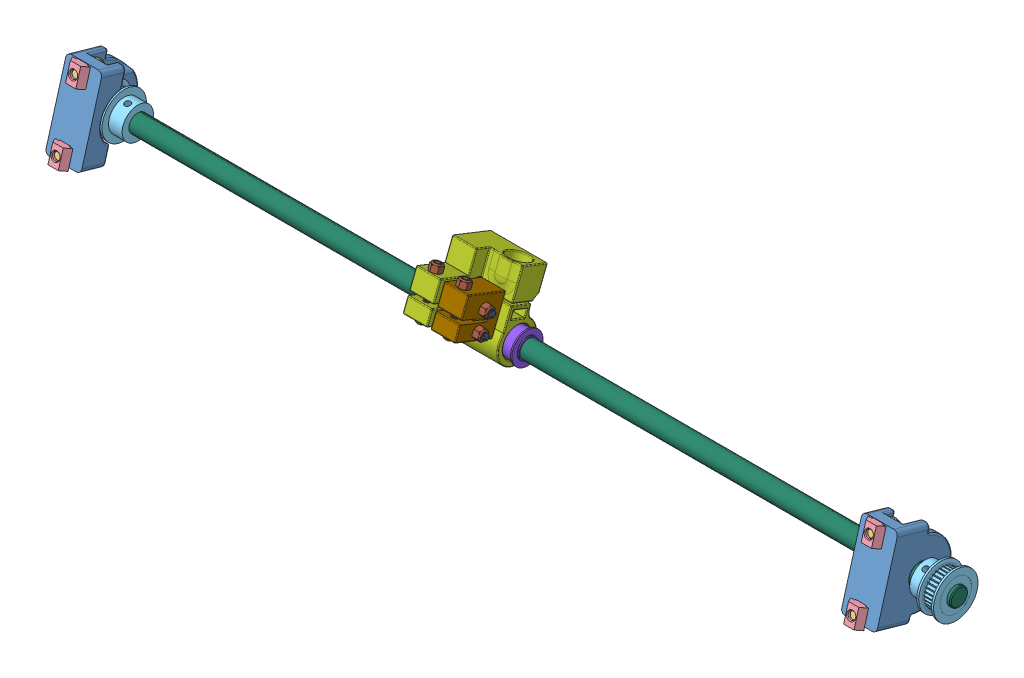
SolidWorks assembly XY_Axis_B, configuration Driven Axis. Lengths in mm.
Overall size (487 72.97 60.62).
36 component instances, 16 part files, 12 mates.
Components (placement in the parent):
- SFJ10-458-1: SFJ10-458 [Default] at origin size (458 10 10) (suppressed, hidden)
- 10mm_Rod_End_Bearing_Assembly-1: 10mm_Rod_End_Bearing_Assembly [Default] at (6 5.178 18.2808) x (0 -0.962148 0.272529) z (0 -0.272529 -0.962148) size (48.98 27.53 42.5)
  - Bearing_Holder-1: Bearing_Holder [Default] at origin size (45 20.07 37)
  - 6900ZZ_10x22x6-1: 6900ZZ_10x22x6 [5972K164] at (0 3 19) x (1 0 0) z (0 1 0) size (22 22 6)
  - 5mmX12mm_Buttonhead(McMaster_92095A210)-3: 5mmX12mm_Buttonhead(McMaster_92095A210) [92095A210] at (18 0 10.75) x (-0.866025 -0.5 0) z (0 0 1) size (9.5 9.5 15.22)
  - 5mmX12mm_Buttonhead(McMaster_92095A210)-2: 5mmX12mm_Buttonhead(McMaster_92095A210) [92095A210] at (-18 0 10.75) x (0.866025 0.5 0) z (0 0 1) size (9.5 9.5 15.22)
  - HNTTSN5-5-1: HNTTSN5-5 [Default] at (-18 0 -1.2) x (0 0 1) z (-1 0 0) size (4.3 10 10)
  - HNTTSN5-5-2: HNTTSN5-5 [Default] at (18 0 -1.2) x (0 0 1) z (-1 0 0) size (4.3 10 10)
  - GT2_Aluminum_Timing_Pulley_32_Tooth-1: GT2_Aluminum_Timing_Pulley_32_Tooth [Default] at (0 -0.5 19) x (0 -1 0) z (0.46829 0 -0.883575) size (17.03 24.87 24.87)
  - 10mmx16mmx0.5mm_SHim(McMaster_90214A422)-1: 10mmx16mmx0.5mm_SHim(McMaster_90214A422) [Default] at (0 -0.5 19) x (1 0 0) z (0 1 0) size (16 16 0.5)
- 10mm_Rod_End_Bearing_Assembly-2: 10mm_Rod_End_Bearing_Assembly [Pass Through Version] at (451 5.178 18.2808) x (0 0.962148 -0.272529) z (0 -0.272529 -0.962148) size (48.98 27.53 42.5)
  - Bearing_Holder-1: Bearing_Holder [Passthrough] at origin size (45 20.07 37)
  - 6900ZZ_10x22x6-1: 6900ZZ_10x22x6 [5972K164] at (0 3 19) x (1 0 0) z (0 1 0) size (22 22 6)
  - 5mmX12mm_Buttonhead(McMaster_92095A210)-3: 5mmX12mm_Buttonhead(McMaster_92095A210) [92095A210] at (18 0 10.75) x (-0.866025 -0.5 0) z (0 0 1) size (9.5 9.5 15.22)
  - 5mmX12mm_Buttonhead(McMaster_92095A210)-2: 5mmX12mm_Buttonhead(McMaster_92095A210) [92095A210] at (-18 0 10.75) x (0.866025 0.5 0) z (0 0 1) size (9.5 9.5 15.22)
  - HNTTSN5-5-1: HNTTSN5-5 [Default] at (-18 0 -1.2) x (0 0 1) z (-1 0 0) size (4.3 10 10)
  - HNTTSN5-5-2: HNTTSN5-5 [Default] at (18 0 -1.2) x (0 0 1) z (-1 0 0) size (4.3 10 10)
  - GT2_Aluminum_Timing_Pulley_32_Tooth-1: GT2_Aluminum_Timing_Pulley_32_Tooth [Default] at (0 -0.5 19) x (0 -1 0) z (0.46829 0 -0.883575) size (17.03 24.87 24.87)
  - 10mmx16mmx0.5mm_SHim(McMaster_90214A422)-1: 10mmx16mmx0.5mm_SHim(McMaster_90214A422) [Default] at (0 -0.5 19) x (1 0 0) z (0 1 0) size (16 16 0.5)
- XY_Axis_Belt_Tensioner_B-1: XY_Axis_Belt_Tensioner_B [Default] at (187.7262 29.7805 -17.15) x (0 0.367652 0.929963) z (1 0 0) size (46.04 45 41.58)
  - XY Axis Belt Tensioner B-1: XY Axis Belt Tensioner B [Default] at origin size (46 45 32.06)
  - a_7z41mpsb10m-1: a_7z41mpsb10m [Default] at (5 34 53.6866) x (1 0 0) z (0 1 0) size (17.4 11.55 17.4)
  - a_7z41mpsb10m-2: a_7z41mpsb10m [Default] at (5 34 15.25) x (1 0 0) z (0 -1 0) size (17.4 11.55 17.4)
  - XY Axis Belt Tensioner End-1: XY Axis Belt Tensioner End [Default] at (0 0 29.2) size (22.6 21 13.6)
  - 3mmX35mm_Sockethead(McMaster_91290A135)-1: 3mmX35mm_Sockethead(McMaster_91290A135) [91290A135] at (28.1 28.85 51) size (5.5 5.5 38.26)
  - 3mmX35mm_Sockethead(McMaster_91290A135)-2: 3mmX35mm_Sockethead(McMaster_91290A135) [91290A135] at (28.1 18.85 51) size (5.5 5.5 38.26)
  - 3mm_Hex_Nylock_Nut(McMaster_90576A102)-1: 3mm_Hex_Nylock_Nut(McMaster_90576A102) [90576A102] at (28.1 28.85 45.2) x (1 0 0) z (0 -1 0) size (5.5 4.1 6.35)
  - 3mm_Hex_Nylock_Nut(McMaster_90576A102)-2: 3mm_Hex_Nylock_Nut(McMaster_90576A102) [90576A102] at (28.1 18.85 45.2) x (1 0 0) z (0 -1 0) size (5.5 4.1 6.35)
  - 3mmX25mm_Buttonhead(McMaster_91239A126)-1: 3mmX25mm_Buttonhead(McMaster_91239A126) [91239A126] at (36 34.5 38.4) x (1 0 0) z (0 1 0) size (5.7 5.7 27.01)
  - 3mmX25mm_Buttonhead(McMaster_91239A126)-2: 3mmX25mm_Buttonhead(McMaster_91239A126) [91239A126] at (36 34.5 22.8) x (1 0 0) z (0 1 0) size (5.7 5.7 27.01)
  - 3mm_Hex_Nylock_Nut(McMaster_90576A102)-3: 3mm_Hex_Nylock_Nut(McMaster_90576A102) [90576A102] at (36 11.85 22.8) x (-0.89673 0 -0.442578) z (-0.442578 0 0.89673) size (5.5 4.1 6.35)
  - 3mm_Hex_Nylock_Nut(McMaster_90576A102)-4: 3mm_Hex_Nylock_Nut(McMaster_90576A102) [90576A102] at (36 11.85 38.4) x (-0.836969 0 -0.54725) z (-0.54725 0 0.836969) size (5.5 4.1 6.35)
  - 5mm_Hex_Nut(McMaster_90591A146)-1: 5mm_Hex_Nut(McMaster_90591A146) [90591A146] at (8.7 21.5 39.6) size (8 4.31 9.24)
  - 5mmX16mm_Buttonhead(McMaster_91239A232)-1: 5mmX16mm_Buttonhead(McMaster_91239A232) [91239A232] at (8.7 3.25 39.6) x (-0.995484 0 0.094925) z (0 -1 0) size (9.5 9.5 19.24)
- SFJ10-483-1: SFJ10-483 [Default] at origin
- GT2_Aluminum_Timing_Pulley_32_Tooth-1: GT2_Aluminum_Timing_Pulley_32_Tooth [Default] at (481.0004 0 0) x (-1 0 0) z (0 -0.913908 -0.405921) size (17.03 24.87 24.87)
Mates (geometry in assembly coordinates):
- Concentric1: concentric aligned: cylinder of SFJ10-458-1 through (458 0 0) axis (-1 0 0) radius 5; cylinder of 10mm_Rod_End_Bearing_Assembly-1/6900ZZ_10x22x6-1 through (0.5 0 0) axis (-1 0 0) radius 5
- Concentric2: concentric anti-aligned: cylinder of SFJ10-458-1 through (458 0 0) axis (-1 0 0) radius 5; cylinder of ? through (457.5 0 0) axis (1 0 0) radius 5
- Distance1: distance = 425 mm anti-aligned: plane of 10mm_Rod_End_Bearing_Assembly-1/Bearing_Holder-1 through (16 14.3374 -22.7692) normal (1 0 0); plane of 10mm_Rod_End_Bearing_Assembly-2/Bearing_Holder-1 through (441 -24.1485 -11.8681) normal (-1 0 0)
- Distance2: distance = 212.5 mm anti-aligned: plane of 10mm_Rod_End_Bearing_Assembly-1/Bearing_Holder-1 through (16.5 22.3708 -14.9514) normal (1 0 0); plane of SFJ10-458-1 through (229 0 0) normal (-1 0 0)
- Coincident3: coincident aligned: plane of 10mm_Rod_End_Bearing_Assembly-1/Bearing_Holder-1 through (-1.5 -14.0649 23.7314) normal (0 0.272529 0.962148); plane of 10mm_Rod_End_Bearing_Assembly-2/Bearing_Holder-1 through (458.5 24.421 12.8302) normal (0 0.272529 0.962148)
- Concentric3: concentric anti-aligned: cylinder of SFJ10-458-1 through (458 0 0) axis (-1 0 0) radius 5; cylinder of XY_Axis_Belt_Tensioner_B-1/a_7z41mpsb10m-1 through (208.3291 0 0) axis (1 0 0) radius 5
- Coincident4: coordinate: point of ?
- Concentric4: concentric anti-aligned: cylinder of XY_Axis_Belt_Tensioner_B-1/a_7z41mpsb10m-1 through (230.0728 0 0) axis (1 0 0) radius 5; cylinder of SFJ10-483-1 through (483 0 0) axis (-1 0 0) radius 5
- Concentric5: concentric aligned: cylinder of 10mm_Rod_End_Bearing_Assembly-1/GT2_Aluminum_Timing_Pulley_32_Tooth-1 through (37.7004 0 0) axis (-1 0 0) radius 5.01; cylinder of SFJ10-483-1 through (483 0 0) axis (-1 0 0) radius 5
- Concentric6: concentric anti-aligned: cylinder of 10mm_Rod_End_Bearing_Assembly-2/6900ZZ_10x22x6-1 through (457 0 0) axis (1 0 0) radius 5; cylinder of SFJ10-483-1 through (483 0 0) axis (-1 0 0) radius 5
- Distance3: distance = 1 mm anti-aligned: plane of 10mm_Rod_End_Bearing_Assembly-1/Bearing_Holder-1 through (-1 0 0) normal (1 0 0); plane of SFJ10-483-1 through (0 0 0) normal (-1 0 0)
- Concentric7: concentric anti-aligned: cylinder of SFJ10-483-1 through (483 0 0) axis (-1 0 0) radius 5; cylinder of GT2_Aluminum_Timing_Pulley_32_Tooth-1 through (449.7999 0 0) axis (1 0 0) radius 5.01
